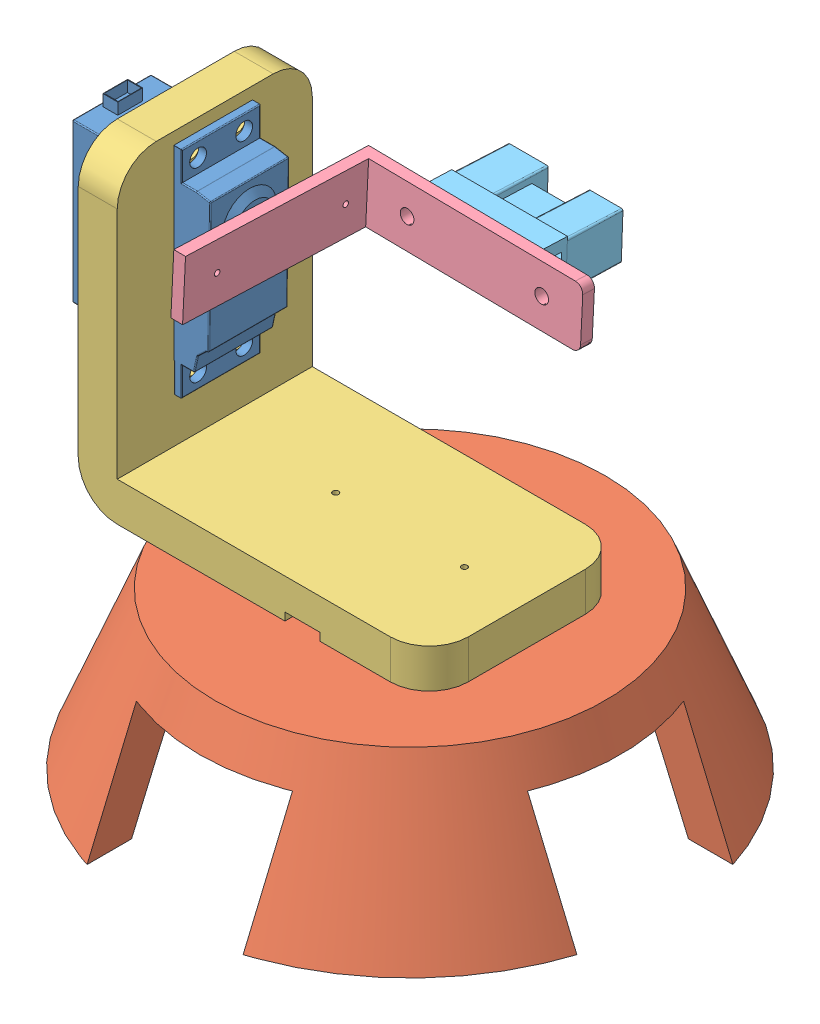
SolidWorks assembly Assembly, configuration Default. Lengths in mm.
Overall size (126.11 134.42 125.58).
6 component instances, 5 part files, 11 mates.
Components (placement in the parent):
- servo motor-1: servo motor [Default] at (-65.853 1.8885 16.4159) size (55.24 41.08 20.19)
- Stand-1: Stand [Default] at (-45.974 -33.1115 26.1089) size (125.58 40 125.58)
- L bracket Servo-1: L bracket Servo [Default] at (-44.7053 31.3071 20.4619) x (-1 0 0) z (0 0 1) size (90 80 50)
- servo motor-2: servo motor [Default] at (-83.2569 50.3071 49.3838) x (0 1 0) z (0 0 -1) size (55.24 41.08 20.19)
- L Bracket sensor-1: L Bracket sensor [Default] at (-24.321 92.9804 16.8105) x (-0.999912 0.013256 0) z (-0.013247 -0.999214 0.037365) size (58 50 15)
- Sensor-1: Sensor [Default] at (-39.6615 79.66 14.314) x (1 -0.000011 -0.000495) z (-0.000007 0.999302 -0.037361) size (44.75 21.6 16.37)
Mates (geometry in assembly coordinates):
- Coincident1: coincident: plane of servo motor-1 through (-65.853 1.8885 36.6089) normal (0 0 1); plane of Stand-1 through (-66.474 -3.1115 36.6089) normal (0 0 -1)
- Coincident2: coincident: plane of servo motor-1 through (-65.853 1.8885 36.6089) normal (0 -1 0); plane of Stand-1 through (-45.974 1.8885 26.1089) normal (0 1 0)
- Coincident3: coincident: plane of servo motor-1 through (-17.974 1.8885 36.6089) normal (1 0 0); plane of Stand-1 through (-17.974 1.8885 36.6089) normal (-1 0 0)
- Parallel2: parallel: plane of Stand-1 through (-45.974 6.8885 26.1089) normal (0 1 0); plane of L bracket Servo-1 through (-44.7053 21.3071 20.4619) normal (0 -1 0)
- Coincident6: coincident: plane of L bracket Servo-1 through (-123.2569 50.3071 38.8838) normal (0 1 0); plane of servo motor-2 through (-83.2569 50.3071 29.1908) normal (0 -1 0)
- Coincident8: coincident: plane of L bracket Servo-1 through (-83.2569 101.3071 13.8838) normal (1 0 0); plane of servo motor-2 through (-83.2569 50.3071 29.1908) normal (-1 0 0)
- Coincident9: coincident: plane of L bracket Servo-1 through (-123.2569 91.3071 49.3838) normal (0 0 -1); plane of servo motor-2 through (-83.2569 50.3071 49.3838) normal (0 0 1)
- Coincident10: coincident: plane of L Bracket sensor-1 through (-24.3225 92.8683 13.8126) normal (-0.000495 -0.037361 -0.999302); plane of Sensor-1 through (-39.6615 79.66 14.314) normal (0.000495 0.037361 0.999302)
- Concentric1: concentric: cylinder of L Bracket sensor-1 through (-21.02 79.7719 17.3027) axis (-0.000495 -0.037361 -0.999302) radius 1.75; cylinder of Sensor-1 through (-21.0223 79.6037 12.8058) axis (0.000495 0.037361 0.999302) radius 1.61
- Concentric2: concentric: cylinder of servo motor-2 through (-68.255 81.2202 39.2873) axis (-0.999912 0.013256 0) radius 2.921; cylinder of L Bracket sensor-1 through (-68.255 81.2202 39.2873) axis (-0.999912 0.013256 0) radius 5
- Coincident12: coincident: plane of servo motor-2 through (-68.6674 50.1137 49.3838) normal (0.999912 -0.013256 0); plane of L Bracket sensor-1 through (-68.255 81.2202 39.2873) normal (-0.999912 0.013256 0)
